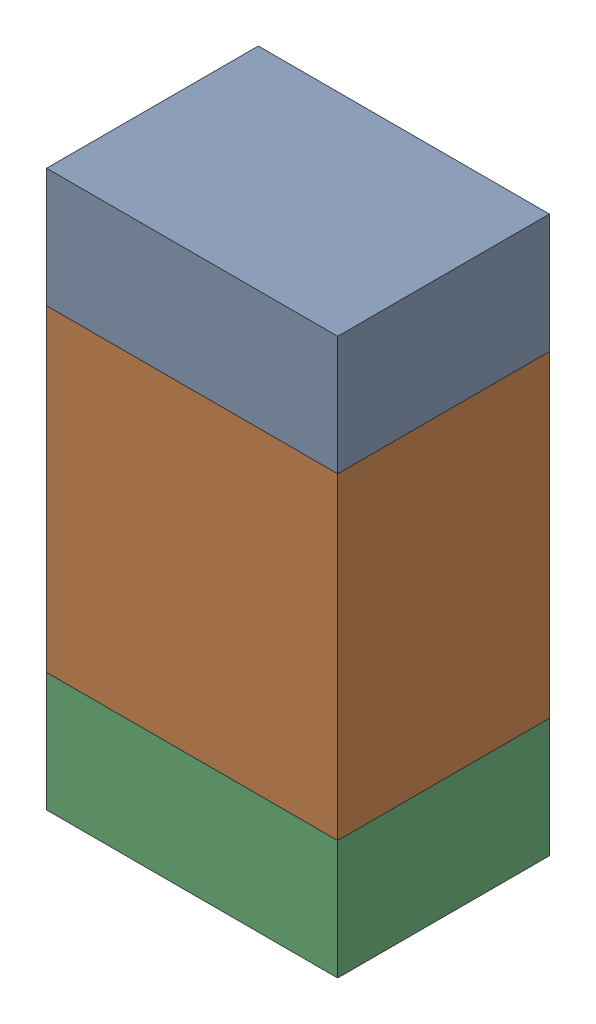
SolidWorks assembly R503_2PCB, configuration Default. Lengths in mm.
Overall size (0.55 1.05 0.4).
6 component instances, 2 part files, 0 mates.
Components (placement in the parent):
- 846483288-1: 846483288 [Default] at (153.9001 85.9124 0) size (0.55 0.22 0.4)
  - Extruded_12-1: Extruded_12 [Default] at origin size (0.55 0.22 0.4)
- 846483424-1: 846483424 [Default] at (153.9001 85.4999 0) size (0.55 0.6 0.4)
  - Extruded_13-1: Extruded_13 [Default] at origin size (0.55 0.6 0.4)
- 846483288-2: 846483288 [Default] at (153.9001 85.0874 0) size (0.55 0.22 0.4)
  - Extruded_12-1: Extruded_12 [Default] at origin size (0.55 0.22 0.4)
